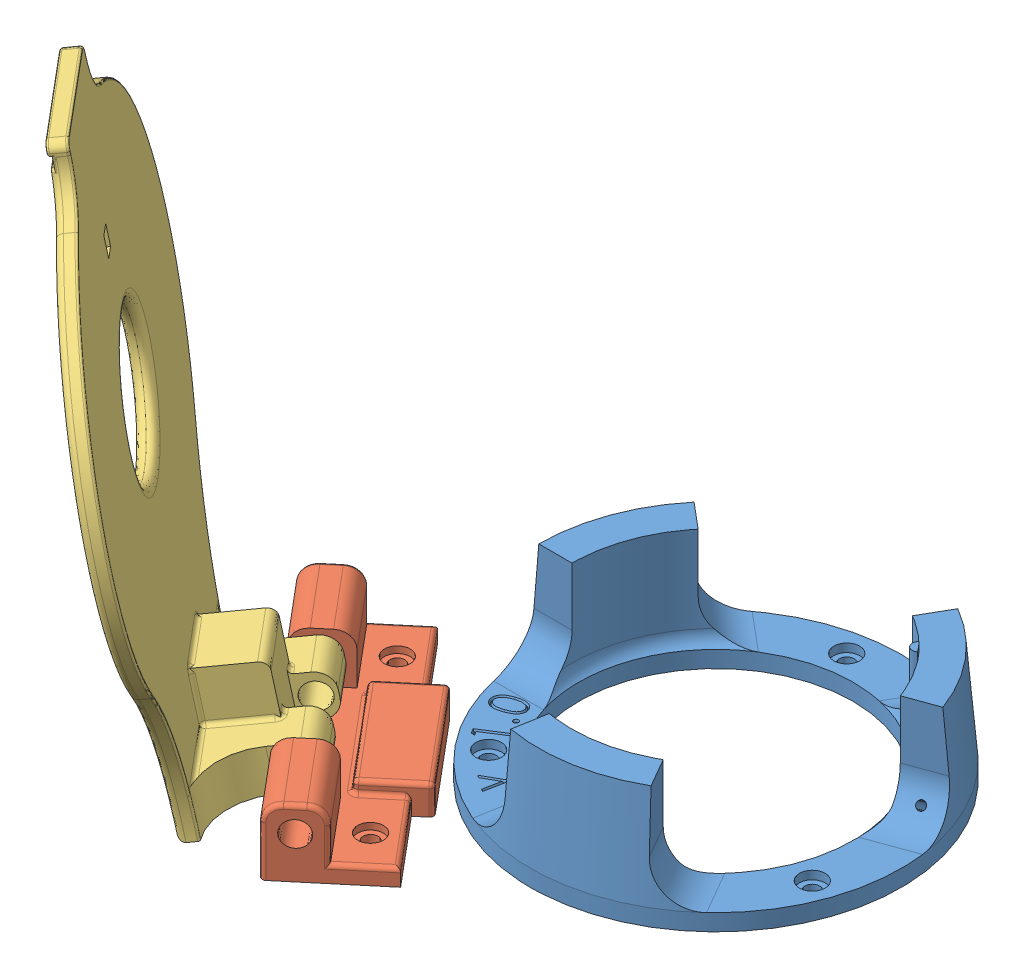
SolidWorks assembly HelicalDeployerBiggerSpringBiggerDowel, configuration Default. Lengths in mm.
3 component instances, 3 part files, 7 mates.
Components (placement in the parent):
- HelicalBaseBiggerDiameterSpring-1: HelicalBaseBiggerDiameterSpring [Default] at origin size (44.83 15 44.6)
- CenterLidBaseBiggerDowel-1: CenterLidBaseBiggerDowel [Default] at (-24.0078 0 20.145) x (0.766044 0 -0.642788) z (0.642788 0 0.766044) size (15.04 8 36)
- HelicalDeployerLid_v1_1-1: HelicalDeployerLid_v1_1 [Default] at (-37.6206 37.413 31.698) x (-0.133022 0.984808 0.111619) z (0.642788 0 0.766044) size (68.54 13.02 54)
Mates (geometry in assembly coordinates):
- Coincident1: coincident: point of HelicalBaseBiggerDiameterSpring-1; point of CenterLidBaseBiggerDowel-1
- Parallel1: parallel anti-aligned: line of HelicalBaseBiggerDiameterSpring-1 through (13.2526 0 -11.1202) axis (-0.766044 0 0.642788); line of CenterLidBaseBiggerDowel-1 through (-28.6041 0 24.0017) axis (0.766044 0 -0.642788)
- Concentric1: concentric aligned: circle of CenterLidBaseBiggerDowel-1; circle of CenterLidBiggerDowel-1
- Coincident2: coincident anti-aligned: plane of CenterLidBaseBiggerDowel-1 through (-23.3975 8 30.2066) normal (-0.642788 0 -0.766044); plane of HelicalDeployerLid_v1_1-1 through (-18.6618 4.6464 26.2329) normal (0.642788 0 0.766044)
- Parallel2: parallel aligned: plane of HelicalBaseBiggerDiameterSpring-1 through (0 0 0) normal (0 -1 0); plane of CenterLidBaseBiggerDowel-1 through (-24.0078 0 20.145) normal (0 -1 0)
- Hinge1: hinge = 1.396263 rad anti-aligned: cylinder of CenterLidBaseBiggerDowel-1 through (-37.8761 5 8.2845) axis (-0.642788 0 -0.766044) radius 1.5; cylinder of CenterLidBiggerDowel-1 through (-21.0994 5 28.2783) axis (0.642788 0 0.766044) radius 1.55; plane of CenterLidBiggerDowel-1 through (-19.258 2.8853 26.7332) normal (0.642788 0 0.766044); plane of CenterLidBiggerDowel-1 through (-23.3975 8 30.2066) normal (-0.642788 0 -0.766044); plane of CenterLidBaseBiggerDowel-1 through (-24.0078 3.45 20.145) normal (0 1 0); plane of CenterLidBaseBiggerDowel-1 through (-37.5383 65.2184 28.3654) normal (0.754407 0.173648 -0.633022)
- Hinge2: hinge = 3.141593 rad anti-aligned: cylinder of HelicalDeployerLid_v1_1-1 through (-21.0994 5 28.2783) axis (0.642788 0 0.766044) radius 1.5; cylinder of CenterLidBaseBiggerDowel-1 through (-37.8761 5 8.2845) axis (-0.642788 0 -0.766044) radius 1.5; plane of CenterLidBaseBiggerDowel-1 through (-23.3975 8 30.2066) normal (-0.642788 0 -0.766044); plane of HelicalDeployerLid_v1_1-1 through (-18.6618 4.6464 26.2329) normal (0.642788 0 0.766044); plane of HelicalDeployerLid_v1_1-1 through (-62.245 47.0729 49.0968) normal (0.541675 0.707107 -0.454519); plane of CenterLidBaseBiggerDowel-1 through (-24.0078 3.45 20.145) normal (0 1 0)
